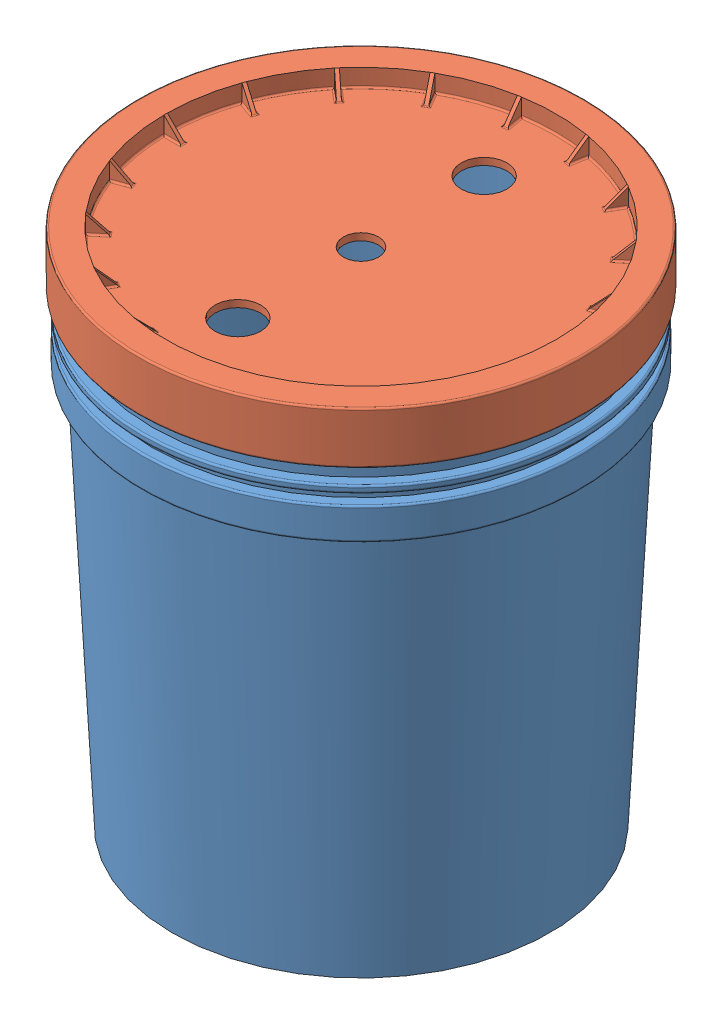
SolidWorks assembly Bucket with Lid, configuration Default. Lengths in mm.
Overall size (321.54 373.38 321.54).
2 component instances, 2 part files, 4 mates.
Components (placement in the parent):
- Bucket-1: Bucket [Default] at origin size (316.46 368.3 316.46)
- Lid^Bucket with Lid-1: Lid^Bucket with Lid [Default] at origin size (321.54 37.48 321.54) (virtual)
Mates (geometry in assembly coordinates):
- InPlace1: in place: plane of ? through (0 0 0) normal (0 0 1); moOrthogonalPlaneRef_w of ? through (0 0 0) normal (0 1 0); plane of ? through (0 0 0) normal (1 0 0); unknown of ?
- Coincident1: coincident aligned: 
- Coincident2: coincident aligned: plane of Lid^Bucket with Lid-1 through (0 0 0) normal (0 1 0)
- Coincident3: coincident anti-aligned: plane of Lid^Bucket with Lid-1 through (0 0 0) normal (1 0 0)
